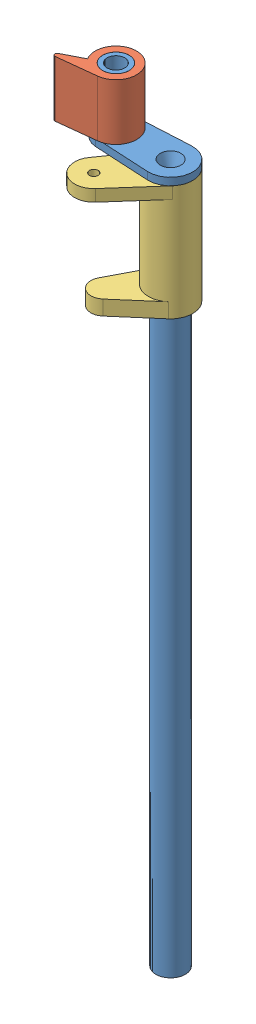
SolidWorks assembly barra, configuration Predeterminado. Lengths in mm.
Overall size (43.48 255.5 34.79).
3 component instances, 3 part files, 4 mates.
Components (placement in the parent):
- barra-1: barra [Predeterminado] at (-117.166 -94.6628 255.5001) size (32.5 255.5 15)
- barra3-1: barra3 [Predeterminado] at (-161.5525 141.8372 253.7172) x (-0.993807 0 0.111124) z (-0.111124 0 -0.993807) size (20.75 19 14)
- barra u-1: barra u [Predeterminado] at (-120.5246 105.3372 240.7403) x (0.62078 0 -0.783985) z (0.783985 0 0.62078) size (32.5 39 15)
Mates (geometry in assembly coordinates):
- Concéntrica2: concentric anti-aligned: cylinder of barra-1 through (-147.6412 160.8372 253.2855) axis (0 -1 0) radius 4.5; cylinder of barra3-1 through (-147.6412 141.8372 253.2855) axis (0 1 0) radius 4.5
- Coincidente2: coincident anti-aligned: plane of barra-1 through (-147.6412 141.8372 253.2855) normal (0 1 0); plane of barra3-1 through (-147.6412 141.8372 253.2855) normal (0 -1 0)
- Concéntrica3: concentric anti-aligned: cylinder of barra-1 through (-129.1412 139.3372 253.2855) axis (0 -1 0) radius 5; cylinder of barra u-1 through (-129.1412 100.3372 253.2855) axis (0 1 0) radius 5
- Coincidente3: coincident anti-aligned: plane of barra-1 through (-147.6412 139.3372 253.2855) normal (0 -1 0); plane of barra u-1 through (-129.1412 139.3372 253.2855) normal (0 1 0)
